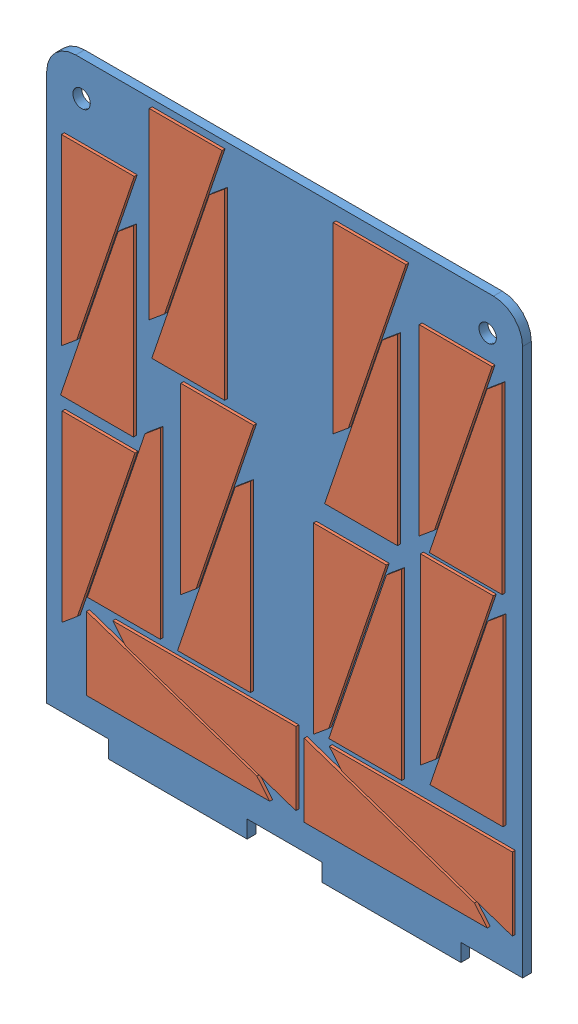
SolidWorks assembly Side X Solar Panel Assembly, configuration Default. Lengths in mm.
Overall size (81.8 102 2).
2 component instances, 2 part files, 3 mates.
Components (placement in the parent):
- Side X Solar Panel-1: Side X Solar Panel [Default] at (-16.9358 6.3906 82.162) size (81.8 102 1.5)
- Side X Solar Cells-1: Side X Solar Cells [Default] at (-16.8304 9.3918 83.662) x (1 0.000585 0) z (0 0 1) size (77.64 92.98 0.5)
Mates (geometry in assembly coordinates):
- Coincident1: coincident: plane of Side X Solar Panel-1 through (-16.9358 6.3906 83.662) normal (0 0 1); plane of Side X Solar Cells-1 through (-16.8304 10.5553 83.662) normal (0 0 -1)
- Distance1: distance = 3 mm: line of Side X Solar Cells-1 through (61.8642 65.2192 83.662) axis (0 1 0); line of Side X Solar Panel-1 through (64.8642 9.3906 83.662) axis (0 1 0)
- Distance2: distance = 7.9 mm: line of Side X Solar Cells-1 through (27.848 14.2906 83.662) axis (1 0 0); line of Side X Solar Panel-1 through (30.4092 6.3906 83.662) axis (1 0 0)
